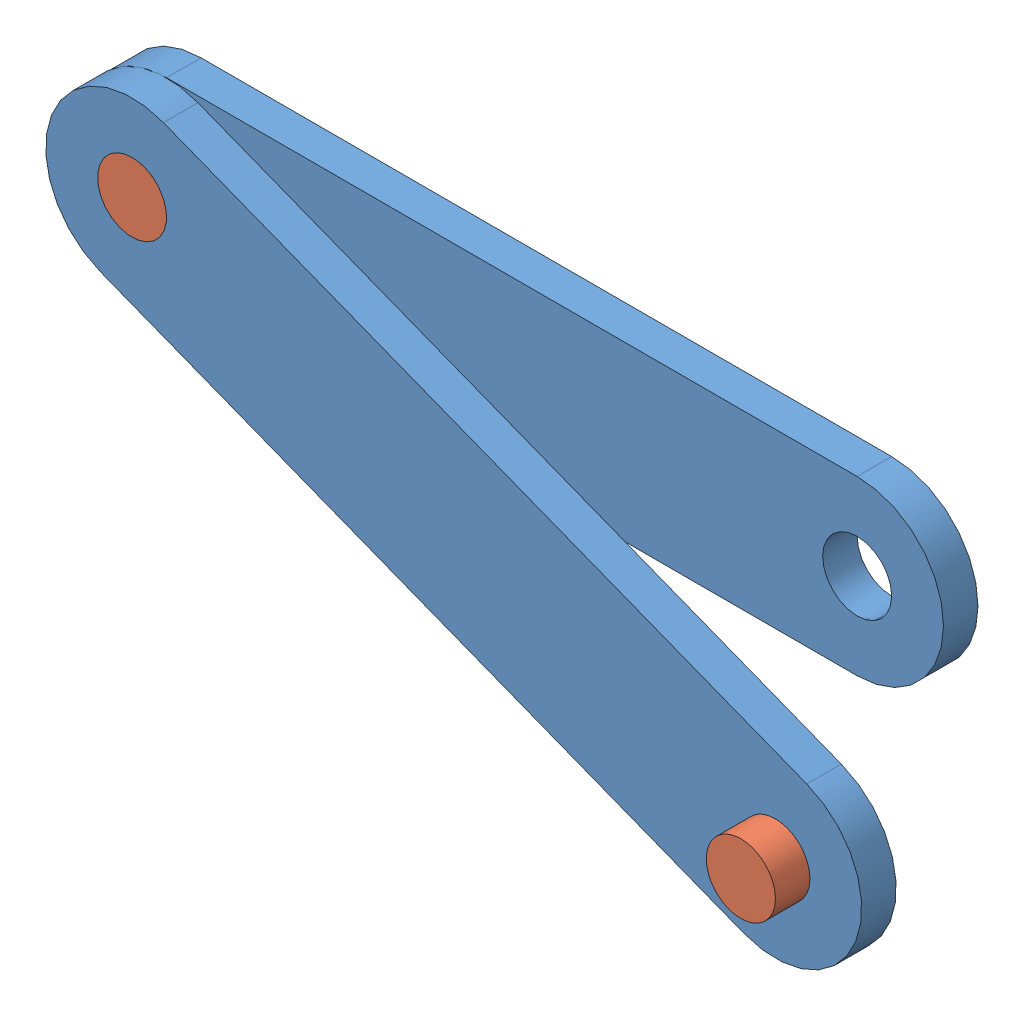
SolidWorks assembly Сборка2, configuration По умолчанию. Lengths in mm.
Overall size (257.38 137.47 30).
4 component instances, 2 part files, 2 mates.
Components (placement in the parent):
- example 1-1: example 1 [По умолчанию] at origin size (250 50 10)
- exapmle2-1: exapmle2 [По умолчанию] at origin size (20 20 20)
- example 1-2: example 1 [По умолчанию] at (0 0 10) x (0.931564 -0.363578 0) z (0 0 1) size (250 50 10)
- exapmle2-2: exapmle2 [По умолчанию] at (186.3128 -72.7155 10) size (20 20 20)
Mates (geometry in assembly coordinates):
- Совпадение1: coincident aligned: circle of exapmle2-1; circle of example 1-2
- Совпадение2: coincident aligned: circle of example 1-2; circle of exapmle2-2
